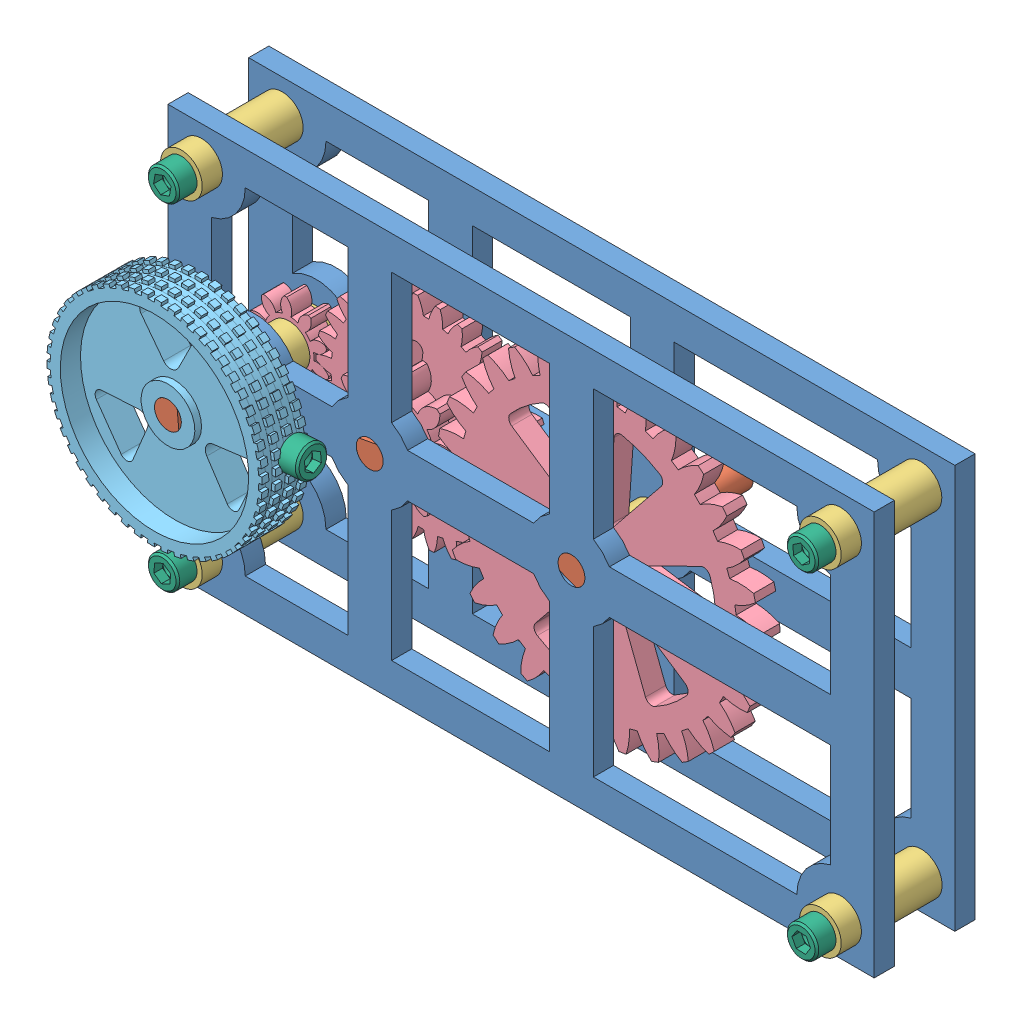
SolidWorks assembly gearbox assembly, configuration Default. Lengths in mm.
Overall size (112.4 62.08 37).
37 component instances, 6 part files, 47 mates.
Components (placement in the parent):
- plate-1: plate [Default] at (41.5755 67.9007 75.5311) size (105 60 3)
- first subassembly-1: first subassembly [Default] at (-14.9194 57.7675 106.4334) x (-0.092507 0.995712 0) z (0 0 -1) size (12 11.53 25)
  - axle-1: axle [25 mm tall] at (8.7951 14.8723 5.9022) size (4 3.5 25)
  - spacer-1: spacer [4.2 mm ID] at (8.7951 14.8723 26.9022) x (-0.0222 0.999754 0) z (0 0 1) size (6.2 6.2 1)
  - spacer-2: spacer [5mm tall] at (8.7951 14.8723 18.9022) x (-0.292793 -0.956176 0) z (0 0 1) size (6.2 6.2 5)
  - root_gear copy-1: root_gear copy [10T 1.0Mod] at (8.7951 14.8723 23.9022) size (12 11.53 3)
- second subassembly-1: second subassembly [Default] at (24.8204 61.7166 87.9504) x (-0.983661 -0.180029 0) z (0 0 -1) size (32 31.89 15)
  - root_gear copy-1: root_gear copy [30T 1.0Mod] at (4.5377 7.1173 5.4193) size (32 31.89 3)
  - root_gear copy-2: root_gear copy [10T 1.5Mod] at (4.5377 7.1173 4.4193) x (-1 0 0) z (0 0 -1) size (18 17.3 3)
  - axle-1: axle [15 mm tall] at (4.5377 7.1173 -2.5807) size (4 3.5 15)
  - spacer-1: spacer [4.2 mm ID] at (4.5377 7.1173 4.4193) size (6.2 6.2 1)
  - spacer-2: spacer [4.2 mm ID] at (4.5377 7.1173 0.4193) size (6.2 6.2 1)
  - spacer-3: spacer [4.2 mm ID] at (4.5377 7.1173 8.4193) size (6.2 6.2 1)
- third subassembly-1: third subassembly [Default] at (65.6341 84.8071 62.4949) x (-0.930768 0.365611 0) z (0 0 1) size (48 47.84 25)
  - root_gear copy-1: root_gear copy [30T 1.5Mod] at (9.2311 21.7899 21.0363) size (48 47.84 3)
  - axle-1: axle [25 mm tall] at (9.2311 21.7899 3.0363) size (4 3.5 25)
  - spacer-1: spacer [4.2 mm ID] at (9.2311 21.7899 24.0363) size (6.2 6.2 1)
  - spacer-2: spacer [5mm tall] at (9.2311 21.7899 16.0363) x (0.014596 -0.999893 0) z (0 0 1) size (6.2 6.2 5)
- plate-2: plate [Default] at (41.5755 67.9007 87.5311) size (105 60 3)
- knob-1: knob [Default] at (-0.9245 67.9007 95.5311) x (0 0 1) z (-0.995712 -0.092507 0) size (7 32 31.99)
- spacer-1: spacer [2.85 mm ID] at (89.0755 42.9007 78.5311) size (6.2 6.2 9)
- socket head cap screw_ai-4: socket head cap screw_ai [HX-SHCS 0.112-40x0.375x0.375-N] at (-5.9245 92.9007 72.6863) x (0 0 1) z (-1 0 0) size (12.37 4.65 4.65)
- socket head cap screw_ai-5: socket head cap screw_ai [HX-SHCS 0.112-40x0.375x0.375-N] at (89.0755 42.9007 72.6863) x (0 0 1) z (-1 0 0) size (12.37 4.65 4.65)
- socket head cap screw_ai-6: socket head cap screw_ai [HX-SHCS 0.112-40x0.375x0.375-N] at (-5.9245 42.9007 72.6863) x (0 0 1) z (-1 0 0) size (12.37 4.65 4.65)
- socket head cap screw_ai-8: socket head cap screw_ai [HX-SHCS 0.112-40x0.375x0.375-N] at (89.0262 92.7638 72.5165) x (0 0 1) z (-1 0 0) size (12.37 4.65 4.65)
- spacer-2: spacer [2.85 mm ID] at (89.0262 92.7638 78.5311) size (6.2 6.2 9)
- spacer-3: spacer [2.85 mm ID] at (-5.9245 42.9007 78.5311) size (6.2 6.2 9)
- spacer-4: spacer [2.85 mm ID] at (-5.9245 92.9007 78.5311) size (6.2 6.2 9)
- socket head cap screw_ai-9: socket head cap screw_ai [HX-SHCS 0.112-40x0.375x0.375-N] at (89.0755 42.9007 96.3759) x (0 0 -1) z (0.889346 0.457234 0) size (12.37 4.65 4.65)
- socket head cap screw_ai-10: socket head cap screw_ai [HX-SHCS 0.112-40x0.375x0.375-N] at (-5.9245 92.9007 96.3759) x (0 0 -1) z (0.985291 -0.170887 0) size (12.37 4.65 4.65)
- socket head cap screw_ai-11: socket head cap screw_ai [HX-SHCS 0.112-40x0.375x0.375-N] at (89.0755 92.9007 96.3759) x (0 0 -1) z (0.558123 -0.829758 0) size (12.37 4.65 4.65)
- socket head cap screw_ai-12: socket head cap screw_ai [HX-SHCS 0.112-40x0.375x0.375-N] at (-5.9245 42.9007 96.3759) x (0 0 -1) z (0.996009 -0.089255 0) size (12.37 4.65 4.65)
- spacer-5: spacer [3 mm ID] at (-5.9245 42.9007 93.5311) x (-0.923728 -0.383049 0) z (0 0 -1) size (6.2 6.2 3)
- spacer-6: spacer [3 mm ID] at (-5.9245 92.9007 93.5311) x (-0.923728 -0.383049 0) z (0 0 -1) size (6.2 6.2 3)
- spacer-7: spacer [3 mm ID] at (89.0755 42.9007 93.5311) x (-0.923728 -0.383049 0) z (0 0 -1) size (6.2 6.2 3)
- spacer-8: spacer [3 mm ID] at (89.0755 92.9007 90.5311) x (0.2571 0.966385 0) z (0 0 1) size (6.2 6.2 3)
- socket head cap screw_ai-18: socket head cap screw_ai [HX-SHCS 0.112-40x0.5625x0.5625-N] at (17.6279 69.6243 97.5311) x (-0.995712 -0.092507 0) z (0.000075 -0.000807 1) size (17.13 4.65 4.65)
Mates (geometry in assembly coordinates):
- Concentric1: concentric anti-aligned: cylinder of plate-1 through (49.0755 67.9007 75.5311) axis (0 0 1) radius 2; cylinder of third subassembly-1/axle-1 through (49.0755 67.9007 90.5311) axis (0 0 -1) radius 2
- Concentric2: concentric anti-aligned: circle of plate-1; circle of third subassembly-1/spacer-2
- Coincident2: coincident anti-aligned: plane of plate-1 through (41.5755 67.9007 78.5311) normal (0 0 1); plane of third subassembly-1/spacer-2 through (49.0755 67.9007 78.5311) normal (0 0 -1)
- Concentric3: concentric aligned: cylinder of plate-1 through (19.0755 67.9007 75.5311) axis (0 0 1) radius 2; cylinder of second subassembly-1/axle-1 through (19.0755 67.9007 75.5311) axis (0 0 1) radius 2
- Concentric4: concentric aligned: circle of plate-1; circle of second subassembly-1/spacer-3
- Coincident3: coincident anti-aligned: plane of plate-1 through (41.5755 67.9007 78.5311) normal (0 0 1); plane of second subassembly-1/spacer-3 through (19.0755 67.9007 78.5311) normal (0 0 -1)
- Concentric5: concentric aligned: cylinder of plate-1 through (-0.9245 67.9007 75.5311) axis (0 0 1) radius 2; cylinder of first subassembly-1/axle-1 through (-0.9245 67.9007 75.5311) axis (0 0 1) radius 2
- Concentric6: concentric aligned: circle of plate-1; circle of first subassembly-1/spacer-1
- GearMate7: gear = 3 : 1 mm: line of first subassembly-1/root_gear copy-1 through (-0.9245 67.9007 79.5311) axis (0 0 1); line of second subassembly-1/root_gear copy-1 through (19.0755 67.9007 79.5311) axis (0 0 -1)
- GearMate9: gear = 3 : 1 mm: line of second subassembly-1/root_gear copy-2 through (19.0755 67.9007 86.5311) axis (0 0 -1); line of third subassembly-1/root_gear copy-1 through (49.0755 67.9007 86.5311) axis (0 0 1)
- Coincident5: coincident aligned: cylinder of first subassembly-1/axle-1 through (-0.9245 67.9007 75.5311) axis (0 0 1) radius 2; circle of plate-2
- Concentric7: concentric aligned: cylinder of second subassembly-1/axle-1 through (19.0755 67.9007 75.5311) axis (0 0 1) radius 2; cylinder of plate-2 through (19.0755 67.9007 87.5311) axis (0 0 1) radius 2
- Concentric8: concentric anti-aligned: cylinder of third subassembly-1/axle-1 through (49.0755 67.9007 90.5311) axis (0 0 -1) radius 2; cylinder of plate-2 through (49.0755 67.9007 87.5311) axis (0 0 1) radius 2
- Concentric13: concentric anti-aligned: cylinder of plate-1 through (-5.9245 92.9007 75.5311) axis (0 0 1) radius 1.5; cylinder of socket head cap screw_ai-4 through (-5.9245 92.9007 40.9363) axis (0 0 -1) radius 2.3241
- Coincident9: coincident anti-aligned: plane of plate-1 through (41.5755 67.9007 75.5311) normal (0 0 -1); plane of socket head cap screw_ai-4 through (-5.9245 95.2248 75.5311) normal (0 0 1)
- Concentric141: concentric anti-aligned: cylinder of plate-1 through (89.0755 42.9007 75.5311) axis (0 0 1) radius 1.5; cylinder of socket head cap screw_ai-5 through (89.0755 42.9007 40.9363) axis (0 0 -1) radius 2.3241
- Coincident101: coincident anti-aligned: plane of plate-1 through (41.5755 67.9007 75.5311) normal (0 0 -1); plane of socket head cap screw_ai-5 through (89.0755 45.2248 75.5311) normal (0 0 1)
- Concentric15: concentric anti-aligned: cylinder of plate-1 through (-5.9245 42.9007 75.5311) axis (0 0 1) radius 1.5; cylinder of socket head cap screw_ai-6 through (-5.9245 42.9007 40.9363) axis (0 0 -1) radius 2.3241
- Coincident11: coincident anti-aligned: plane of plate-1 through (41.5755 67.9007 75.5311) normal (0 0 -1); plane of socket head cap screw_ai-6 through (-5.9245 45.2248 75.5311) normal (0 0 1)
- Concentric16: concentric aligned: cylinder of spacer-1 through (89.0755 42.9007 87.5311) axis (0 0 -1) radius 1.425; cylinder of socket head cap screw_ai-5 through (89.0755 42.9007 40.9363) axis (0 0 -1) radius 1.4224
- Coincident12: coincident anti-aligned: plane of plate-1 through (41.5755 67.9007 78.5311) normal (0 0 1); plane of spacer-1 through (89.0755 42.9007 78.5311) normal (0 0 -1)
- Concentric17: concentric aligned: cylinder of socket head cap screw_ai-8 through (89.0262 92.7638 40.7665) axis (0 0 -1) radius 1.4224; cylinder of spacer-2 through (89.0262 92.7638 87.5311) axis (0 0 -1) radius 1.425
- Coincident13: coincident anti-aligned: plane of plate-1 through (41.5755 67.9007 78.5311) normal (0 0 1); plane of spacer-2 through (89.0262 92.7638 78.5311) normal (0 0 -1)
- Concentric18: concentric aligned: cylinder of socket head cap screw_ai-6 through (-5.9245 42.9007 40.9363) axis (0 0 -1) radius 1.4224; cylinder of spacer-3 through (-5.9245 42.9007 87.5311) axis (0 0 -1) radius 1.425
- Coincident14: coincident anti-aligned: plane of plate-1 through (41.5755 67.9007 78.5311) normal (0 0 1); plane of spacer-3 through (-5.9245 42.9007 78.5311) normal (0 0 -1)
- Concentric19: concentric aligned: cylinder of socket head cap screw_ai-4 through (-5.9245 92.9007 40.9363) axis (0 0 -1) radius 1.4224; cylinder of spacer-4 through (-5.9245 92.9007 87.5311) axis (0 0 -1) radius 1.425
- Coincident15: coincident anti-aligned: plane of plate-1 through (41.5755 67.9007 78.5311) normal (0 0 1); plane of spacer-4 through (-5.9245 92.9007 78.5311) normal (0 0 -1)
- Concentric22: concentric anti-aligned: circle of plate-2; circle of spacer-4
- Coincident16: coincident anti-aligned: plane of plate-2 through (41.5755 67.9007 87.5311) normal (0 0 -1); plane of spacer-4 through (-5.9245 92.9007 87.5311) normal (0 0 1)
- Concentric23: concentric aligned: cylinder of plate-2 through (-5.9245 92.9007 87.5311) axis (0 0 1) radius 1.5; cylinder of socket head cap screw_ai-10 through (-5.9245 92.9007 128.1259) axis (0 0 1) radius 1.4224
- Concentric24: concentric aligned: cylinder of plate-2 through (-5.9245 42.9007 87.5311) axis (0 0 1) radius 1.5; cylinder of socket head cap screw_ai-12 through (-5.9245 42.9007 128.1259) axis (0 0 1) radius 1.4224
- Concentric25: concentric aligned: cylinder of plate-2 through (89.0755 92.9007 87.5311) axis (0 0 1) radius 1.5; cylinder of socket head cap screw_ai-11 through (89.0755 92.9007 128.1259) axis (0 0 1) radius 1.4224
- Concentric27: concentric aligned: cylinder of socket head cap screw_ai-9 through (89.0755 42.9007 128.1259) axis (0 0 1) radius 1.4224; cylinder of plate-2 through (89.0755 42.9007 87.5311) axis (0 0 1) radius 1.5
- Coincident17: coincident anti-aligned: circle of plate-2; circle of spacer-8
- Coincident18: coincident aligned: circle of plate-2; circle of spacer-7
- Coincident19: coincident aligned: circle of plate-2; circle of spacer-5
- Concentric28: concentric aligned: cylinder of plate-2 through (-5.9245 92.9007 87.5311) axis (0 0 1) radius 1.5; circle of spacer-6
- Coincident21: coincident anti-aligned: plane of socket head cap screw_ai-10 through (-5.5274 95.1906 93.5311) normal (0 0 -1); plane of spacer-6 through (-5.9245 92.9007 93.5311) normal (0 0 1)
- Coincident22: coincident anti-aligned: plane of socket head cap screw_ai-11 through (91.0039 94.1978 93.5311) normal (0 0 -1); plane of spacer-8 through (89.0755 92.9007 93.5311) normal (0 0 1)
- Coincident23: coincident anti-aligned: plane of socket head cap screw_ai-9 through (88.0128 44.9676 93.5311) normal (0 0 -1); plane of spacer-7 through (89.0755 42.9007 93.5311) normal (0 0 1)
- Coincident24: coincident anti-aligned: plane of socket head cap screw_ai-12 through (-5.7171 45.2155 93.5311) normal (0 0 -1); plane of spacer-5 through (-5.9245 42.9007 93.5311) normal (0 0 1)
- Coincident25: coincident anti-aligned: plane of plate-2 through (41.5755 67.9007 90.5311) normal (0 0 1); plane of spacer-6 through (-5.9245 92.9007 90.5311) normal (0 0 -1)
- Coincident26: coincident anti-aligned: plane of plate-1 through (41.5755 67.9007 78.5311) normal (0 0 1); plane of first subassembly-1/spacer-1 through (-0.9245 67.9007 78.5311) normal (0 0 -1)
- Concentric142: concentric anti-aligned: cylinder of first subassembly-1/axle-1 through (-0.9245 67.9007 75.5311) axis (0 0 1) radius 2; cylinder of knob-1 through (-0.9245 67.9007 95.5311) axis (0 0 -1) radius 2
- Coincident102: coincident anti-aligned: plane of first subassembly-1/axle-1 through (-0.9245 67.9007 100.5311) normal (0 0 1); circle of knob-1
- Coincident105: coincident aligned: plane of first subassembly-1/axle-1 through (0.6914 66.7223 75.5311) normal (0.995712 0.092507 0); circle of socket head cap screw_ai-18
- Concentric146: concentric anti-aligned: cylinder of knob-1 through (-0.9245 67.9007 97.5311) axis (-0.995712 -0.092507 0) radius 1.5; cylinder of socket head cap screw_ai-18 through (49.2417 72.5614 97.5311) axis (0.995712 0.092507 0) radius 1.4224
